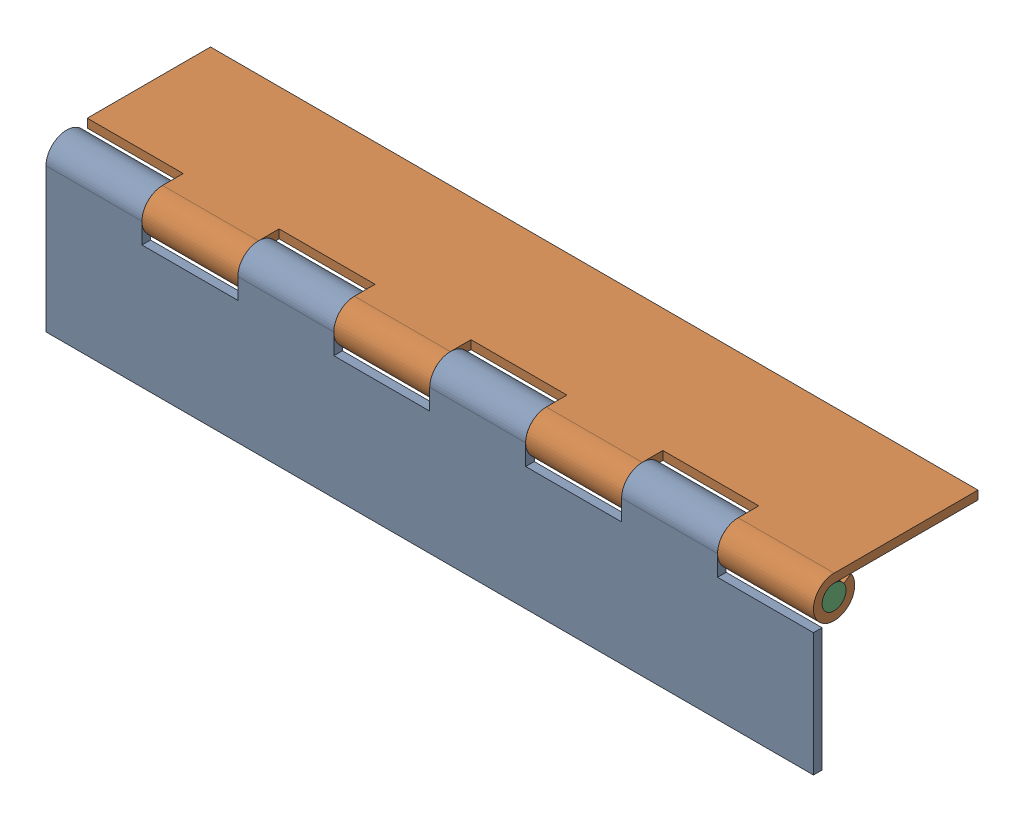
SolidWorks assembly FE-00004-08_ASM, configuration Default. Lengths in mm.
Overall size (203.2 43.56 43.56).
3 component instances, 2 part files, 0 mates.
Components (placement in the parent):
- FE-00004-08-A-1: FE-00004-08-A [Default] at origin size (203.2 43.56 10.92)
- FE-00004-08-A-2: FE-00004-08-A [Default] at (0 5.461 -5.461) x (-1 0 0) z (0 1 0) size (203.2 43.56 10.92)
- FE-00004-08-C-1: FE-00004-08-C [Default] at (0 0 -5.461) size (203.2 6.35 6.35)
